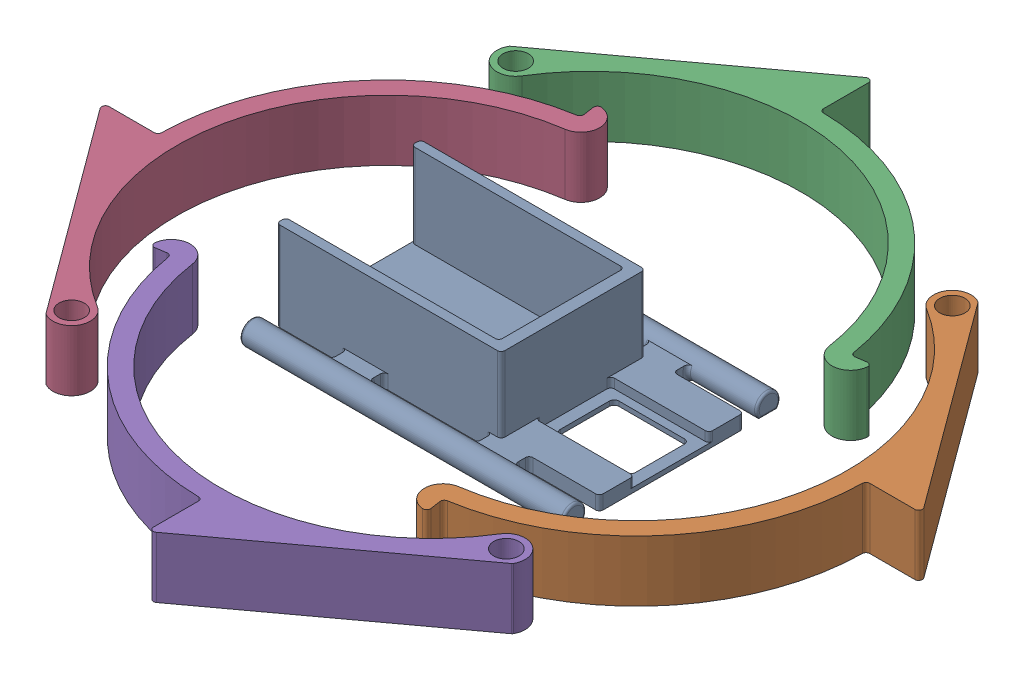
SolidWorks assembly ArmBandforPrinting v1, configuration Default. Lengths in mm.
Overall size (184.15 19 182.18).
5 component instances, 2 part files, 8 mates.
Components (placement in the parent):
- HRand9V mount v1-1: HRand9V mount v1 [Default] at (-5.9846 -7.5369 6.2622) size (69 19 46.49)
- Arm Clamp v2-1: Arm Clamp v2 [Default] at (17.9286 -7.5369 -5.3974) x (0.851164 0 0.524899) z (-0.524899 0 0.851164) size (54.95 13 94.53)
- Arm Clamp v2-2: Arm Clamp v2 [Default] at (-6.5555 -7.5369 -19.9881) x (0.524899 0 -0.851164) z (0.851164 0 0.524899) size (54.95 13 94.53)
- Arm Clamp v2-3: Arm Clamp v2 [Default] at (-23.8427 -7.5369 6.1535) x (-0.851164 0 -0.524899) z (0.524899 0 -0.851164) size (54.95 13 94.53)
- Arm Clamp v2-4: Arm Clamp v2 [Default] at (-0.7173 -7.5369 19.8129) x (-0.524899 0 0.851164) z (-0.851164 0 -0.524899) size (54.95 13 94.53)
Mates (geometry in assembly coordinates):
- Coincident1: coincident: plane of HRand9V mount v1-1 through (-5.9846 -7.5369 6.2622) normal (0 -1 0); plane of Arm Clamp v2-2 through (-6.5555 -7.5369 -19.9881) normal (0 -1 0)
- Coincident2: coincident: plane of HRand9V mount v1-1 through (-5.9846 -7.5369 6.2622) normal (0 -1 0); plane of Arm Clamp v2-3 through (-23.8427 -7.5369 6.1535) normal (0 -1 0)
- Coincident3: coincident: plane of HRand9V mount v1-1 through (-5.9846 -7.5369 6.2622) normal (0 -1 0); plane of Arm Clamp v2-4 through (-0.7173 -7.5369 19.8129) normal (0 -1 0)
- Coincident4: coincident: plane of HRand9V mount v1-1 through (-5.9846 -7.5369 6.2622) normal (0 -1 0); plane of Arm Clamp v2-1 through (17.9286 -7.5369 -5.3974) normal (0 -1 0)
- Parallel1: parallel aligned: plane of HRand9V mount v1-1 through (-37.8318 11.4631 15.8244) normal (0 0 1); plane of Arm Clamp v2-1 through (17.9286 5.4631 -5.3974) normal (0 0 1)
- Parallel2: parallel aligned: plane of HRand9V mount v1-1 through (10.1682 -33.9377 -7.5756) normal (1 0 0); plane of Arm Clamp v2-2 through (-6.5555 5.4631 -19.9881) normal (1 0 0)
- Parallel3: parallel anti-aligned: plane of HRand9V mount v1-1 through (10.1682 -33.9377 -7.5756) normal (1 0 0); plane of Arm Clamp v2-4 through (-0.7173 5.4631 19.8129) normal (-1 0 0)
- Parallel4: parallel anti-aligned: plane of HRand9V mount v1-1 through (-37.8318 11.4631 15.8244) normal (0 0 1); plane of Arm Clamp v2-3 through (-23.8427 5.4631 6.1535) normal (0 0 -1)
